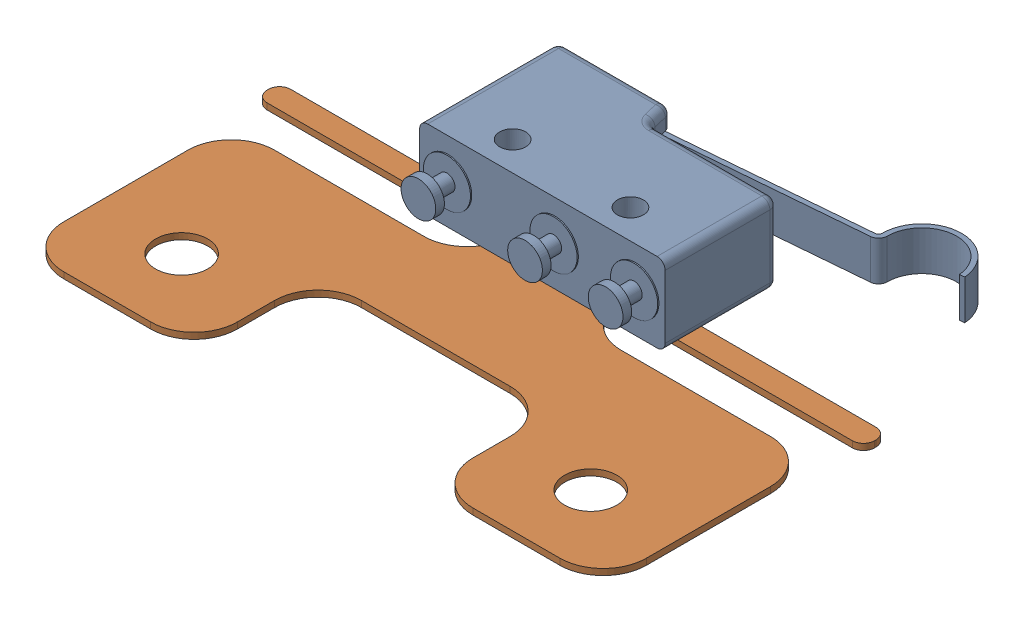
SolidWorks assembly 01 switch sub, configuration Default. Lengths in mm.
Overall size (49 6.9 34.1).
2 component instances, 2 part files, 3 mates.
Components (placement in the parent):
- microswitch-1: microswitch [Default] at origin size (31.4 6.4 17.9)
- microswitch holder-1: microswitch holder [Default] at (9.9 -3.2 8.6) size (49 0.5 27.9)
Mates (geometry in assembly coordinates):
- Coincident1: coincident anti-aligned: plane of microswitch-1 through (0 -3.2 -11.2) normal (0 -1 0); plane of microswitch holder-1 through (19.4 -3.2 18.6) normal (0 1 0)
- Concentric1: concentric: cylinder of microswitch-1 through (14.65 -13.2 -2.35) axis (0 1 0) radius 1.05; point of microswitch holder-1
- Concentric2: concentric: cylinder of microswitch-1 through (5.15 -13.2 -2.35) axis (0 1 0) radius 1.05; point of microswitch holder-1
